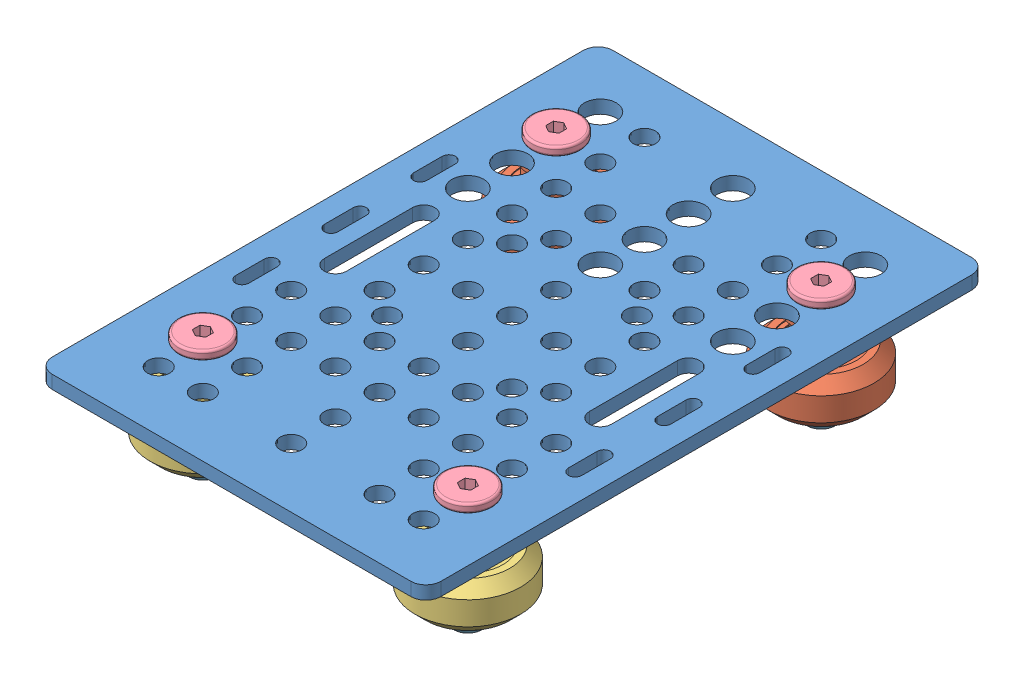
SolidWorks assembly VSlotGantryAssembly, configuration Default. Lengths in mm.
Overall size (93.76 27 127).
13 component instances, 5 part files, 24 mates.
Components (placement in the parent):
- 80mm gantry plate-1: 80mm gantry plate [Default] at (44.5371 61.8398 103.0297) x (0 0 -1) z (0 -1 0) size (127 88 3)
- V-Wheel Solid Wheel-1: V-Wheel Solid Wheel [Default] at (-1.0034 46.1688 62.2277) x (-0.989884 0 0.141879) z (0.141879 0 0.989884) size (23.9 20 23.9)
- V-Wheel Solid Wheel-2: V-Wheel Solid Wheel [Default] at (62.1652 46.1688 72.4683) x (-0.663258 0 0.748391) z (0.748391 0 0.663258) size (23.9 20 23.9)
- V-Wheel Solid Wheel - spacer-1: V-Wheel Solid Wheel - spacer [Default] at (89.4926 46.1688 138.7307) x (0.889827 0 -0.456298) z (-0.456298 0 -0.889827) size (23.9 17 23.9)
- V-Wheel Solid Wheel - spacer-2: V-Wheel Solid Wheel - spacer [Default] at (23.5413 46.1688 155.7213) x (0.724956 0 0.688795) z (0.688795 0 -0.724956) size (23.9 17 23.9)
- M5x25 low profile screw-1: M5x25 low profile screw [Default] at (14.5371 63.8398 143.0297) x (1 0 0) z (0 -1 0) size (11 11 27)
- M5x25 low profile screw-2: M5x25 low profile screw [Default] at (74.5371 63.8398 63.0297) x (1 0 0) z (0 -1 0) size (11 11 27)
- M5x25 low profile screw-3: M5x25 low profile screw [Default] at (14.5371 63.8398 63.0297) x (1 0 0) z (0 -1 0) size (11 11 27)
- M5x25 low profile screw-4: M5x25 low profile screw [Default] at (74.5371 63.8398 143.0297) x (1 0 0) z (0 -1 0) size (11 11 27)
- M5 Nylock-1: M5 Nylock [Default] at (14.5371 41.8398 143.0297) x (0.938869 0 -0.344275) z (0 -1 0) size (8.02 9.26 5)
- M5 Nylock-2: M5 Nylock [Default] at (74.5371 41.8398 143.0297) x (0.988292 0 -0.152575) z (0 -1 0) size (8.02 9.26 5)
- M5 Nylock-3: M5 Nylock [Default] at (14.5371 41.8398 63.0297) x (0.987803 0 -0.15571) z (0 -1 0) size (8.02 9.26 5)
- M5 Nylock-4: M5 Nylock [Default] at (74.5371 41.8398 63.0297) x (0.988771 0 -0.149437) z (0 -1 0) size (8.02 9.26 5)
Mates (geometry in assembly coordinates):
- Concentric3: concentric anti-aligned: cylinder of 80mm gantry plate-1 through (74.5371 58.8398 63.0297) axis (0 -1 0) radius 3.6; cylinder of V-Wheel Solid Wheel-2 through (74.5371 61.8398 63.0297) axis (0 1 0) radius 2.5
- Coincident3: coincident anti-aligned: plane of 80mm gantry plate-1 through (44.5371 58.8398 103.0297) normal (0 -1 0); plane of V-Wheel Solid Wheel-2 through (74.5371 58.8398 63.0297) normal (0 1 0)
- Concentric4: concentric anti-aligned: cylinder of 80mm gantry plate-1 through (14.5371 58.8398 63.0297) axis (0 -1 0) radius 3.6; cylinder of V-Wheel Solid Wheel-1 through (14.5371 61.8398 63.0297) axis (0 1 0) radius 2.5
- Coincident4: coincident anti-aligned: plane of 80mm gantry plate-1 through (44.5371 58.8398 103.0297) normal (0 -1 0); plane of V-Wheel Solid Wheel-1 through (14.5371 58.8398 63.0297) normal (0 1 0)
- Concentric7: concentric anti-aligned: cylinder of V-Wheel Solid Wheel-1 through (14.5371 61.8398 63.0297) axis (0 1 0) radius 2.5; cylinder of M5x25 low profile screw-3 through (14.5371 49.3398 63.0297) axis (0 -1 0) radius 2.5
- Coincident7: coincident anti-aligned: plane of 80mm gantry plate-1 through (44.5371 61.8398 103.0297) normal (0 1 0); plane of M5x25 low profile screw-3 through (14.5371 61.8398 68.5297) normal (0 -1 0)
- Concentric8: concentric anti-aligned: cylinder of V-Wheel Solid Wheel-2 through (74.5371 61.8398 63.0297) axis (0 1 0) radius 2.5; cylinder of M5x25 low profile screw-2 through (74.5371 49.3398 63.0297) axis (0 -1 0) radius 2.5
- Coincident8: coincident anti-aligned: plane of 80mm gantry plate-1 through (44.5371 61.8398 103.0297) normal (0 1 0); plane of M5x25 low profile screw-2 through (74.5371 61.8398 68.5297) normal (0 -1 0)
- Concentric9: concentric anti-aligned: cylinder of M5x25 low profile screw-4 through (74.5371 49.3398 143.0297) axis (0 -1 0) radius 2.5; cylinder of M5 Nylock-2 through (74.5371 41.8398 143.0297) axis (0 1 0) radius 2.5
- Coincident9: coincident aligned: plane of M5x25 low profile screw-4 through (74.5371 36.8398 145.5297) normal (0 -1 0); plane of M5 Nylock-2 through (74.5371 36.8398 143.0297) normal (0 -1 0)
- Concentric10: concentric anti-aligned: cylinder of M5x25 low profile screw-1 through (14.5371 49.3398 143.0297) axis (0 -1 0) radius 2.5; cylinder of M5 Nylock-1 through (14.5371 41.8398 143.0297) axis (0 1 0) radius 2.5
- Coincident10: coincident aligned: plane of M5x25 low profile screw-1 through (14.5371 36.8398 145.5297) normal (0 -1 0); plane of M5 Nylock-1 through (14.5371 36.8398 143.0297) normal (0 -1 0)
- Concentric11: concentric anti-aligned: cylinder of M5x25 low profile screw-3 through (14.5371 49.3398 63.0297) axis (0 -1 0) radius 2.5; cylinder of M5 Nylock-3 through (14.5371 41.8398 63.0297) axis (0 1 0) radius 2.5
- Coincident11: coincident aligned: plane of M5x25 low profile screw-3 through (14.5371 36.8398 65.5297) normal (0 -1 0); plane of M5 Nylock-3 through (14.5371 36.8398 63.0297) normal (0 -1 0)
- Concentric12: concentric anti-aligned: cylinder of M5x25 low profile screw-2 through (74.5371 49.3398 63.0297) axis (0 -1 0) radius 2.5; cylinder of M5 Nylock-4 through (74.5371 41.8398 63.0297) axis (0 1 0) radius 2.5
- Coincident12: coincident aligned: plane of M5x25 low profile screw-2 through (74.5371 36.8398 65.5297) normal (0 -1 0); plane of M5 Nylock-4 through (74.5371 36.8398 63.0297) normal (0 -1 0)
- Concentric13: concentric aligned: cylinder of 80mm gantry plate-1 through (74.5371 58.8398 143.0297) axis (0 -1 0) radius 2.5; cylinder of M5x25 low profile screw-4 through (74.5371 49.3398 143.0297) axis (0 -1 0) radius 2.5
- Coincident13: coincident anti-aligned: plane of 80mm gantry plate-1 through (44.5371 61.8398 103.0297) normal (0 1 0); plane of M5x25 low profile screw-4 through (74.5371 61.8398 148.5297) normal (0 -1 0)
- Concentric14: concentric aligned: cylinder of V-Wheel Solid Wheel - spacer-1 through (74.5371 52.8398 143.0297) axis (0 -1 0) radius 2.55; cylinder of M5x25 low profile screw-4 through (74.5371 49.3398 143.0297) axis (0 -1 0) radius 2.5
- Coincident14: coincident anti-aligned: plane of 80mm gantry plate-1 through (44.5371 58.8398 103.0297) normal (0 -1 0); plane of V-Wheel Solid Wheel - spacer-1 through (74.5371 58.8398 143.0297) normal (0 1 0)
- Coincident15: coincident anti-aligned: plane of 80mm gantry plate-1 through (44.5371 61.8398 103.0297) normal (0 1 0); plane of M5x25 low profile screw-1 through (14.5371 61.8398 148.5297) normal (0 -1 0)
- Concentric15: concentric aligned: cylinder of 80mm gantry plate-1 through (14.5371 58.8398 143.0297) axis (0 -1 0) radius 2.5; cylinder of M5x25 low profile screw-1 through (14.5371 49.3398 143.0297) axis (0 -1 0) radius 2.5
- Concentric16: concentric aligned: cylinder of V-Wheel Solid Wheel - spacer-2 through (14.5371 52.8398 143.0297) axis (0 -1 0) radius 2.55; cylinder of M5x25 low profile screw-1 through (14.5371 49.3398 143.0297) axis (0 -1 0) radius 2.5
- Coincident16: coincident anti-aligned: plane of 80mm gantry plate-1 through (44.5371 58.8398 103.0297) normal (0 -1 0); plane of V-Wheel Solid Wheel - spacer-2 through (14.5371 58.8398 143.0297) normal (0 1 0)
